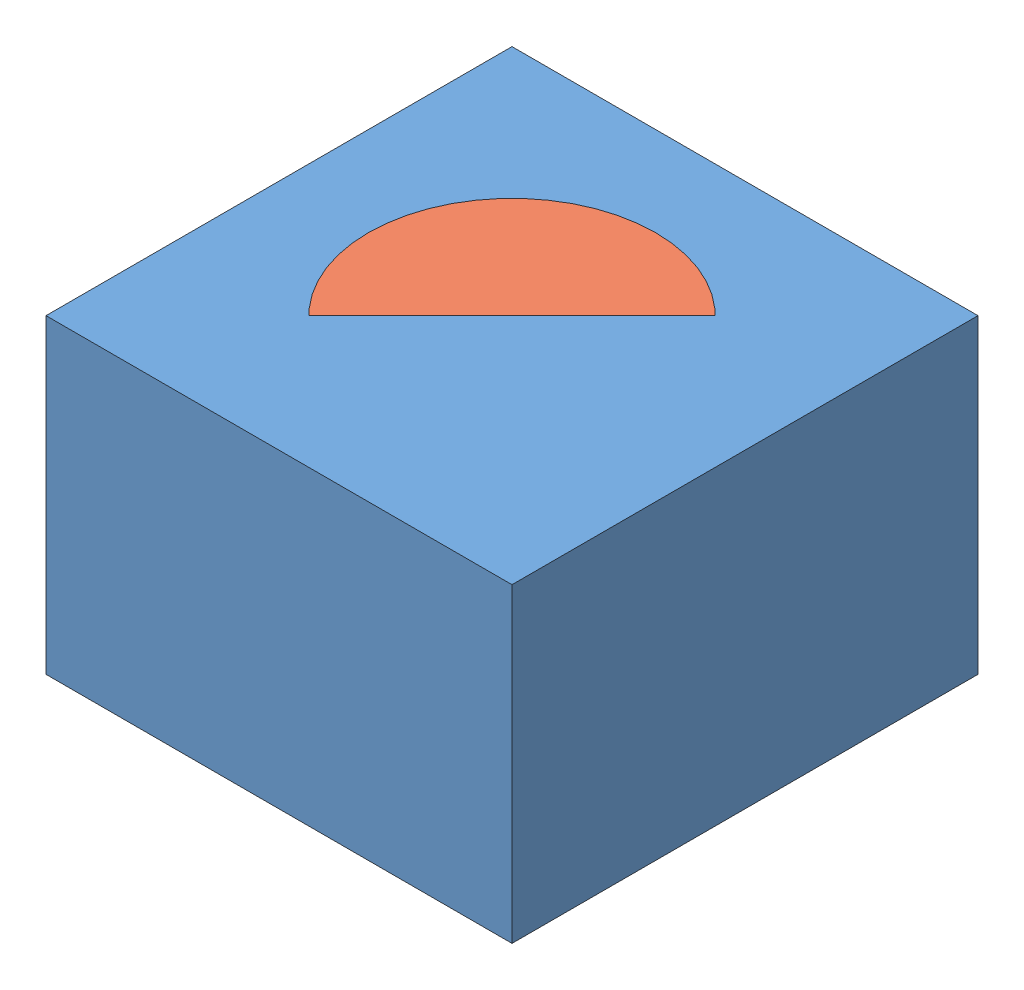
SolidWorks assembly Baugruppe3, configuration Standard. Lengths in mm.
Overall size (30 20 30).
2 component instances, 2 part files, 2 mates.
Components (placement in the parent):
- MoldingFormUmrellaV1_0_0_SAK-1: MoldingFormUmrellaV1_0_0_SAK [Standard] at (-27.8575 -11.2711 30) size (30 20 30)
- one-way valve umbrella seal V3-2: one-way valve umbrella seal V3 [Default] at (-27.8575 8.7289 30) size (18.5 8 18.5)
Mates (geometry in assembly coordinates):
- Konzentrisch1: concentric aligned: cylinder of one-way valve umbrella seal V3-2 through (-27.8575 308.1737 30) axis (0 1 0) radius 9.25
- Abstand1: distance = 0 mm aligned: plane of one-way valve umbrella seal V3-2 through (-27.8575 8.7289 30) normal (0 1 0); plane of MoldingFormUmrellaV1_0_0_SAK-1 through (-27.8575 8.7289 30) normal (0 1 0)
